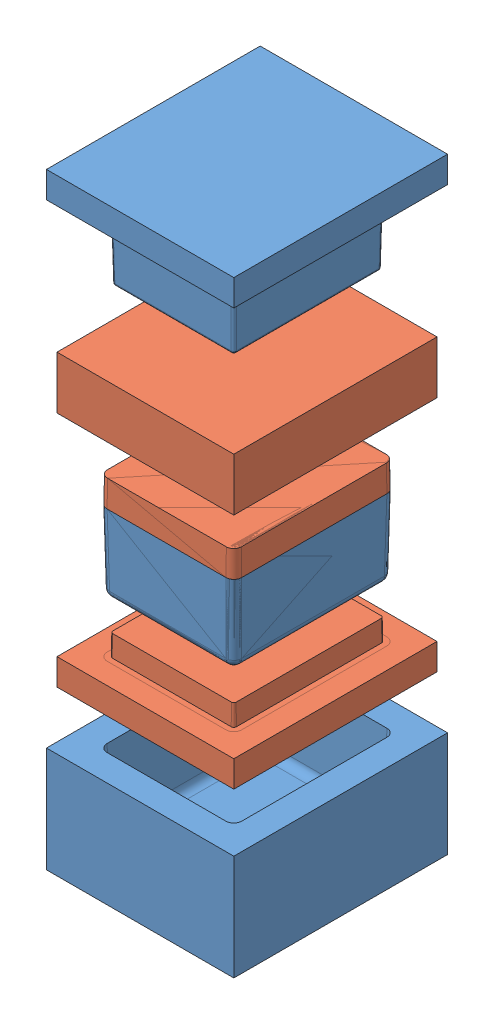
SolidWorks assembly box, configuration Default. Lengths in mm.
Overall size (71.05 230 81.05).
2 component instances, 2 part files, 2 mates.
Components (placement in the parent):
- bottom-1: bottom [Default] at origin size (71.05 230 81.05)
- top-1: top [Default] at (9.39 30 10.9236) size (67.05 110 77.05)
Mates (geometry in assembly coordinates):
- Coincident1: coincident anti-aligned: plane of bottom-1 through (0 30 0) normal (0 1 0); plane of Part5-1 through (2.4768 30 -57.5232) normal (0 -1 0)
- Coincident2: coincident aligned: line of bottom-1 through (50.5237 30 -2.4759) axis (0 0 -1); line of Part5-1 through (50.5237 30 -2.4759) axis (0 0 -1)
